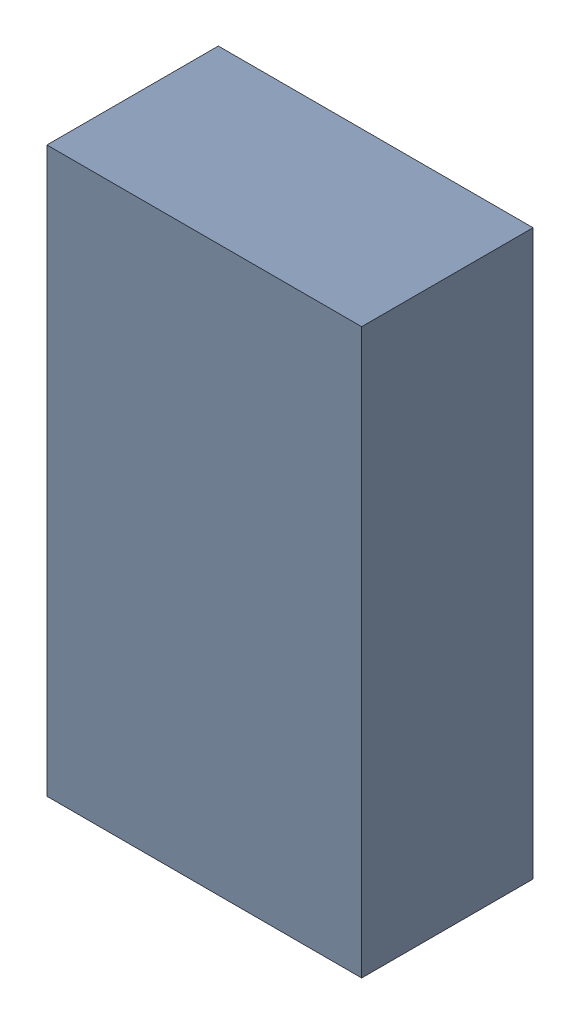
SolidWorks assembly R19, configuration Default. Lengths in mm.
Overall size (1.01 1.81 0.56).
3 component instances, 2 part files, 0 mates.
Components (placement in the parent):
- 1088887696-1: 1088887696 [Default] at (1.75 45.05 -2.194) size (1.01 1.81 0.55)
  - Extruded-29-1: Extruded-29 [Default] at origin size (1.01 1.81 0.55)
- R0603-1: R0603 [Default] at (1.7499 45.0499 -1.644) x (0 -1 0) z (1 0 0) size (1.7 0.56 0.8)
